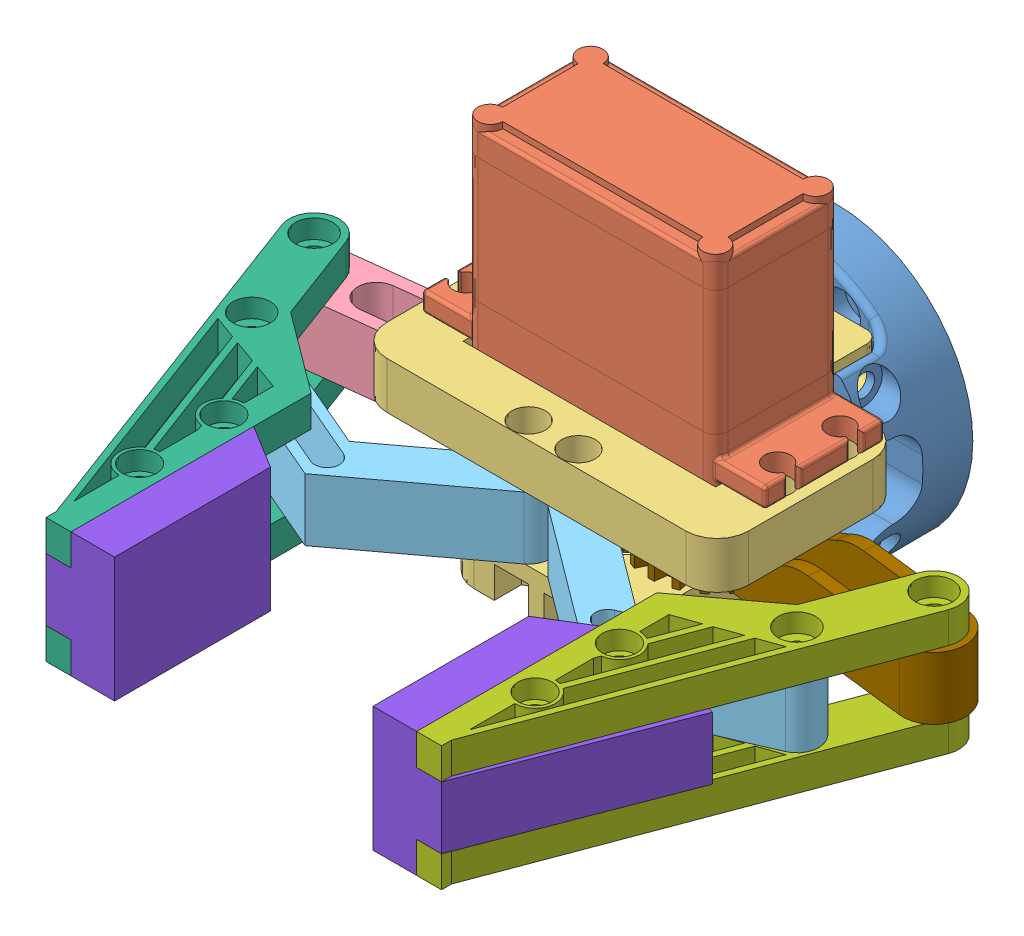
SolidWorks assembly Gripper_without_bolts, configuration Standard. Lengths in mm.
Overall size (111.93 66 94.94).
13 component instances, 9 part files, 27 mates.
Components (placement in the parent):
- Gripper_Frame-1: Gripper_Frame [Standard] at origin size (44 44 16)
- LewanSoul LD-20M  Servo 20kg-1: LewanSoul LD-20M  Servo 20kg [Default] at (-0.05 44 29.25) x (-1 0 0) z (0 0 1) size (55.1 45.65 20.12)
- Gripper_Frame_2-1: Gripper_Frame_2 [Standard] at (0 0 8) size (58 30 40)
- Hebel-2: Hebel [Standard] at (-29.8622 -5 31.594) x (0.993103 0 -0.117243) z (0.117243 0 0.993103) size (56 10 22)
- Hebel_Support-2: Hebel_Support [Standard] at (-4 -5 45.25) x (0.801431 0 -0.598087) z (0.598087 0 0.801431) size (41.64 10 27)
- Gripper_FInger-1: Gripper_FInger [Standard] at (-49.7242 5 33.9389) x (1 0 0.000011) z (-0.000011 0 1) size (26 5 65)
- SpiegelnGripper_FInger-2: SpiegelnGripper_FInger [Standard] at (49.7242 5 33.9389) x (-1 0 0.000011) z (-0.000011 0 -1) size (26 5 65)
- Hebel_Support-3: Hebel_Support [Standard] at (4 5 45.25) x (-0.801431 0 -0.598087) z (-0.598087 0 0.801431) size (41.64 10 27)
- Gripper_FInger-3: Gripper_FInger [Standard] at (-49.7239 -10 33.9397) x (1 0 0.000011) z (-0.000011 0 1) size (26 5 65)
- SpiegelnGripper_FInger-4: SpiegelnGripper_FInger [Standard] at (49.7239 -10 33.9397) x (-1 0 0.000011) z (-0.000011 0 -1) size (26 5 65)
- TPU_Finger-1: TPU_Finger [Standard] at (-31.7245 0 54.9391) x (1 0 0.000011) z (-0.000011 0 1) size (23.04 20 31.78)
- TPU_Finger-2: TPU_Finger [Standard] at (31.7245 0 54.9391) x (-1 0 0.000011) z (0.000011 0 1) size (23.04 20 31.78)
- Hebel_2-1: Hebel_2 [Standard] at (10 5 29.25) x (0.993106 0 0.117223) z (-0.117223 0 0.993106) size (55.75 10 21.49)
Mates (geometry in assembly coordinates):
- Deckungsgleich1: coincident aligned: plane of Gripper_Frame-1 through (0 0 0) normal (0 0 1)
- Deckungsgleich2: coincident aligned: plane of Gripper_Frame-1 through (0 0 0) normal (0 1 0)
- Deckungsgleich3: coincident aligned: plane of Gripper_Frame-1 through (0 0 0) normal (1 0 0)
- Deckungsgleich13: coincident anti-aligned: plane of Gripper_Frame-1 through (0 0 8) normal (0 0 1); plane of Gripper_Frame_2-1 through (-15 15 8) normal (0 0 -1)
- Deckungsgleich14: coincident aligned: plane of Gripper_Frame_2-1 through (0 0 8) normal (1 0 0)
- Deckungsgleich15: coincident aligned: plane of Gripper_Frame_2-1 through (0 0 8) normal (0 1 0)
- Parallel1: parallel anti-aligned: plane of Gripper_Frame-1 through (0 0 8) normal (0 0 1); plane of LewanSoul LD-20M  Servo 20kg-1 through (-20.1 3.5 19.2) normal (0 0 -1)
- Deckungsgleich29: coincident anti-aligned: plane of LewanSoul LD-20M  Servo 20kg-1 through (-25.05 12.5 34.25) normal (0 -1 0); plane of Gripper_Frame_2-1 through (0 12.5 8) normal (0 1 0)
- Deckungsgleich30: coincident anti-aligned: plane of Gripper_Frame_2-1 through (29 -5 15) normal (0 1 0); plane of Hebel-2 through (-49.7242 -5 33.9389) normal (0 -1 0)
- Konzentrisch13: concentric anti-aligned: cylinder of Gripper_Frame_2-1 through (-4 -15 45.25) axis (0 1 0) radius 1.5; cylinder of Hebel_Support-2 through (-4 5 45.25) axis (0 -1 0) radius 1.825
- Deckungsgleich33: coincident anti-aligned: plane of Gripper_Frame_2-1 through (29 -5 15) normal (0 1 0); plane of Hebel_Support-2 through (-4 -5 45.25) normal (0 -1 0)
- Parallel3: parallel anti-aligned: line of Hebel-2 through (-49.138 5 38.9044) axis (0.993103 0 -0.117243); line of Hebel_Support-2 through (-4 5 45.25) axis (-0.993103 0 0.117243)
- Konzentrisch14: concentric aligned: cylinder of Hebel-2 through (-49.7242 5 33.9389) axis (0 -1 0) radius 1.825; cylinder of Gripper_FInger-1 through (-49.7242 10 33.9389) axis (0 -1 0) radius 1.75
- Konzentrisch15: concentric aligned: cylinder of Hebel_Support-2 through (-43.7241 5 49.9397) axis (0 -1 0) radius 1.825; cylinder of Gripper_FInger-1 through (-43.7244 10 49.939) axis (0 -1 0) radius 1.5
- Deckungsgleich34: coincident anti-aligned: plane of Hebel-2 through (-49.7242 5 33.9389) normal (0 1 0); plane of Gripper_FInger-1 through (-49.7242 5 33.9389) normal (0 -1 0)
- Deckungsgleich37: coincident anti-aligned: plane of Hebel_Support-2 through (-4 -5 45.25) normal (0 -1 0); plane of Gripper_FInger-3 through (-49.7239 -5 33.9397) normal (0 1 0)
- Konzentrisch19: concentric aligned: cylinder of Hebel_Support-2 through (-43.7241 5 49.9397) axis (0 -1 0) radius 1.825; cylinder of Gripper_FInger-3 through (-43.7241 -5 49.9397) axis (0 -1 0) radius 1.5
- Deckungsgleich43: coincident anti-aligned: plane of Gripper_FInger-1 through (-49.7242 5 33.9389) normal (0 -1 0); plane of TPU_Finger-1 through (-27.7249 5 94.9392) normal (0 1 0)
- Deckungsgleich44: coincident anti-aligned: plane of Gripper_FInger-1 through (-27.7244 10 51.406) normal (1 0 0.000011); plane of TPU_Finger-1 through (-27.7249 10 94.9392) normal (-1 0 -0.000011)
- Deckungsgleich45: coincident aligned: plane of Gripper_FInger-1 through (-31.7249 10 94.9391) normal (-0.000011 0 1); plane of TPU_Finger-1 through (-31.7249 0 94.9391) normal (-0.000011 0 1)
- Konzentrisch37: concentric aligned: cylinder of Gripper_Frame_2-1 through (10 -15 29.25) axis (0 1 0) radius 1.5; cylinder of Hebel_2-1 through (10 -5 29.25) axis (0 1 0) radius 1.825
- Deckungsgleich56: coincident anti-aligned: plane of Gripper_Frame_2-1 through (29 -5 15) normal (0 1 0); plane of Hebel_2-1 through (10 -5 29.25) normal (0 -1 0)
- Zahnradverknüpfung1: gear = 18 : 18 mm: cylinder of Hebel-2 through (-10.0001 -30.4558 29.2492) axis (0 1 0) radius 9; cylinder of Hebel_2-1 through (10 -30.4558 29.25) axis (0 1 0) radius 9
- Konzentrisch452: concentric aligned: cylinder of Hebel-2 through (-49.7242 5 33.9389) axis (0 -1 0) radius 1.825; cylinder of Gripper_FInger-3 through (-49.7239 -5 33.9397) axis (0 -1 0) radius 1.75
- Konzentrisch453: concentric aligned: cylinder of LewanSoul LD-20M  Servo 20kg-1 through (-10 -1.65 29.25) axis (0 1 0) radius 1; cylinder of Gripper_Frame_2-1 through (-10 -15 29.25) axis (0 1 0) radius 1.5
- Konzentrisch454: concentric aligned: cylinder of Gripper_Frame_2-1 through (10 -15 29.25) axis (0 1 0) radius 1.5; cylinder of Hebel_2-1 through (10 -5 29.25) axis (0 1 0) radius 1.825
- Konzentrisch455: concentric anti-aligned: cylinder of SpiegelnGripper_FInger-2 through (49.7242 10 33.9389) axis (0 -1 0) radius 1.75; cylinder of Hebel_2-1 through (49.7242 -5 33.9389) axis (0 1 0) radius 1.825
